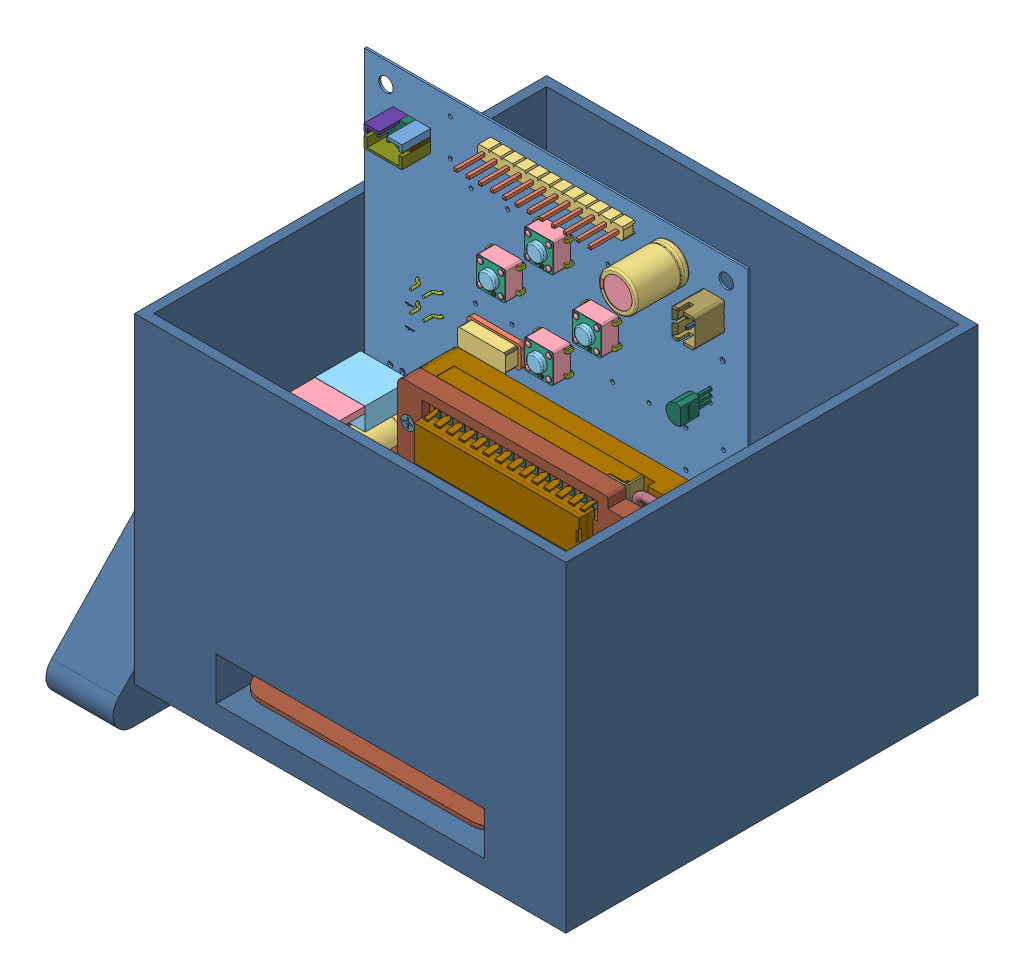
SolidWorks assembly Assem1, configuration Default. Lengths in mm.
Overall size (108 107.56 86.98).
167 component instances, 47 part files, 0 mates.
Components (placement in the parent):
- Clock PCB.step-1: Clock PCB.step [Default] at (-3.837 -6.133 58.5856) size (81.95 80 25.5)
  - Board.step-1: Board.step [Default] at origin size (80 80 0.41)
    - Open CASCADE STEP translator 6.8 1.1.1.step-1: Open CASCADE STEP translator 6.8 1.1.1.step [Default] at (0 0 -0.4115) size (80 80 0.41)
  - XTAL1.step-1: XTAL1.step [Default] at origin size (11.36 4.66 3.61)
    - 6606830048.step-1: 6606830048.step [Default] at (28.0499 41.0499 0) size (11.36 4.66 1.01)
      - Extruded.step-1: Extruded.step [Default] at origin size (11.36 4.66 1.01)
    - 6606829968.step-1: 6606829968.step [Default] at (28.0499 41.0501 1) size (10.05 3.71 2.61)
      - Extruded-0.step-1: Extruded-0.step [Default] at origin size (10.05 3.71 2.61)
  - U2.step-1: U2.step [Default] at origin size (10.5 4.7 16.2)
    - 6606829888.step-1: 6606829888.step [Default] at (7.95 27.55 13.05) size (10.4 1.3 6.65)
      - Extruded-1.step-1: Extruded-1.step [Default] at origin size (10.4 1.3 6.65)
    - 6606829728.step-1: 6606829728.step [Default] at (7.95 25.9 3.5) size (10.5 4.7 9.55)
      - Extruded-2.step-1: Extruded-2.step [Default] at origin size (10.5 4.7 9.55)
  - U1.step-1: U1.step [Default] at origin size (63.7 16.03 14.45)
    - User_Library-ZIF-Socket-28-pin.step-1: User_Library-ZIF-Socket-28-pin.step [Default] at (43.5 28.05 0) x (1 0 0) z (0 0 1) size (63.7 16.03 14.45)
      - Contacts.step-1: Contacts.step [Default] at origin size (34.37 11.24 1.5)
      - Pins001.step-1: Pins001.step [Default] at origin size (33.87 8.47 3)
      - Screw002.step-1: Screw002.step [Default] at origin size (2.8 2.8 2)
      - Bottom-Shape.step-1: Bottom-Shape.step [Default] at origin size (50.4 15.02 8.11)
      - Lever-Tip.step-1: Lever-Tip.step [Default] at origin size (7 4.8 4.8)
      - Top-Shape.step-1: Top-Shape.step [Default] at origin size (50.4 15.02 3.8)
      - Push-Bar.step-1: Push-Bar.step [Default] at origin size (3.85 15.02 3.7)
      - Lever-Bar.step-1: Lever-Bar.step [Default] at origin size (19.2 11.43 1.62)
      - Screw001.step-1: Screw001.step [Default] at origin size (2.8 2.8 2)
  - Q1.step-1: Q1.step [Default] at origin size (3.05 4.08 12.8)
    - BC547-B.step-1: BC547-B.step [Default] at (72 53.1536 7) x (0 1 0) z (0 0 -1) size (4.08 3.05 12.8)
  - P3.step-1: P3.step [Default] at origin size (2.54 10.16 11.54)
    - 61300411121.step-1: 61300411121.step [Default] at (76.2999 22.6001 1.3) x (0 1 0) z (1 0 0) size (10.16 11.54 2.54)
      - 6130xx11121_PIN.step-1: 6130xx11121_PIN.step [Default] at (-3.81 1.5 0) x (1 0 0) z (0 -1 0) size (0.64 0.64 11.54)
      - 6130xx11121_PIN.step-2: 6130xx11121_PIN.step [Default] at (-1.27 1.5 0) x (1 0 0) z (0 -1 0) size (0.64 0.64 11.54)
      - 6130xx11121_PIN.step-3: 6130xx11121_PIN.step [Default] at (1.27 1.5 0) x (1 0 0) z (0 -1 0) size (0.64 0.64 11.54)
      - 6130xx11121_PIN.step-4: 6130xx11121_PIN.step [Default] at (3.81 1.5 0) x (1 0 0) z (0 -1 0) size (0.64 0.64 11.54)
      - 61300411121-3.step-1: 61300411121-3.step [Default] at origin size (10.16 2.54 2.54)
  - P2.step-1: P2.step [Default] at origin size (17.78 2.54 11.54)
    - 61300711121.step-1: 61300711121.step [Default] at (39.9599 3.8999 1.3) x (-1 0 0) z (0 1 0) size (17.78 11.54 2.54)
      - 6130xx11121_PIN-4.step-1: 6130xx11121_PIN-4.step [Default] at (-7.62 1.5 0) x (1 0 0) z (0 -1 0) size (0.64 0.64 11.54)
      - 6130xx11121_PIN-4.step-2: 6130xx11121_PIN-4.step [Default] at (-5.08 1.5 0) x (1 0 0) z (0 -1 0) size (0.64 0.64 11.54)
      - 6130xx11121_PIN-4.step-3: 6130xx11121_PIN-4.step [Default] at (-2.54 1.5 0) x (1 0 0) z (0 -1 0) size (0.64 0.64 11.54)
      - 6130xx11121_PIN-4.step-4: 6130xx11121_PIN-4.step [Default] at (0 1.5 0) x (1 0 0) z (0 -1 0) size (0.64 0.64 11.54)
      - 6130xx11121_PIN-4.step-5: 6130xx11121_PIN-4.step [Default] at (2.54 1.5 0) x (1 0 0) z (0 -1 0) size (0.64 0.64 11.54)
      - 6130xx11121_PIN-4.step-6: 6130xx11121_PIN-4.step [Default] at (5.08 1.5 0) x (1 0 0) z (0 -1 0) size (0.64 0.64 11.54)
      - 6130xx11121_PIN-4.step-7: 6130xx11121_PIN-4.step [Default] at (7.62 1.5 0) x (1 0 0) z (0 -1 0) size (0.64 0.64 11.54)
      - 61300711121-5.step-1: 61300711121-5.step [Default] at origin size (17.78 2.54 2.54)
  - P1.step-1: P1.step [Default] at origin size (30.48 2.54 11.54)
    - 61301211121.step-1: 61301211121.step [Default] at (41.3799 75.6999 1.3) x (-1 0 0) z (0 1 0) size (30.48 11.54 2.54)
      - 6130xx11121_PIN-6.step-1: 6130xx11121_PIN-6.step [Default] at (-13.97 1.5 0) x (1 0 0) z (0 -1 0) size (0.64 0.64 11.54)
      - 6130xx11121_PIN-6.step-2: 6130xx11121_PIN-6.step [Default] at (-11.43 1.5 0) x (1 0 0) z (0 -1 0) size (0.64 0.64 11.54)
      - 6130xx11121_PIN-6.step-3: 6130xx11121_PIN-6.step [Default] at (-8.89 1.5 0) x (1 0 0) z (0 -1 0) size (0.64 0.64 11.54)
      - 6130xx11121_PIN-6.step-4: 6130xx11121_PIN-6.step [Default] at (-6.35 1.5 0) x (1 0 0) z (0 -1 0) size (0.64 0.64 11.54)
      - 6130xx11121_PIN-6.step-5: 6130xx11121_PIN-6.step [Default] at (-3.81 1.5 0) x (1 0 0) z (0 -1 0) size (0.64 0.64 11.54)
      - 6130xx11121_PIN-6.step-6: 6130xx11121_PIN-6.step [Default] at (-1.27 1.5 0) x (1 0 0) z (0 -1 0) size (0.64 0.64 11.54)
      - 6130xx11121_PIN-6.step-7: 6130xx11121_PIN-6.step [Default] at (1.27 1.5 0) x (1 0 0) z (0 -1 0) size (0.64 0.64 11.54)
      - 6130xx11121_PIN-6.step-8: 6130xx11121_PIN-6.step [Default] at (3.81 1.5 0) x (1 0 0) z (0 -1 0) size (0.64 0.64 11.54)
      - 6130xx11121_PIN-6.step-9: 6130xx11121_PIN-6.step [Default] at (6.35 1.5 0) x (1 0 0) z (0 -1 0) size (0.64 0.64 11.54)
      - 6130xx11121_PIN-6.step-10: 6130xx11121_PIN-6.step [Default] at (8.89 1.5 0) x (1 0 0) z (0 -1 0) size (0.64 0.64 11.54)
      - 6130xx11121_PIN-6.step-11: 6130xx11121_PIN-6.step [Default] at (11.43 1.5 0) x (1 0 0) z (0 -1 0) size (0.64 0.64 11.54)
      - 6130xx11121_PIN-6.step-12: 6130xx11121_PIN-6.step [Default] at (13.97 1.5 0) x (1 0 0) z (0 -1 0) size (0.64 0.64 11.54)
      - 61301211121-7.step-1: 61301211121-7.step [Default] at origin size (30.48 2.54 2.54)
  - KEY5.step-1: KEY5.step [Default] at origin size (7.8 5.99 8.11)
    - Switch_TE_1825910-2_eec.step-1: Switch_TE_1825910-2_eec.step [Default] at (68.1 13.85 0) size (7.8 5.99 8.11)
      - Body.step-1: Body.step [Default] at (0 0 4.3) x (0 -1 0) z (0 0 1) size (5.99 5.99 3.9)
      - button.step-1: button.step [Default] at (0 0 4.3) x (0 -1 0) z (0 0 1) size (3.51 3.51 1.1)
      - cover.step-1: cover.step [Default] at (0 0 4.3) x (0 -1 0) z (0 0 1) size (5.99 5.99 0.1)
      - leads.step-1: leads.step [Default] at (0 0 4.3) x (0 -1 0) z (0 0 1) size (5.21 7.8 4.81)
      - circle.step-1: circle.step [Default] at (-2.6803 2.6863 3.6) size (0.4 0.4 0)
      - TE_Connectivity.step-1: TE_Connectivity.step [Default] at (-0.1925 -2.4218 3.6) size (2.27 0.85 0.01)
  - KEY4.step-1: KEY4.step [Default] at origin size (7.8 5.99 8.11)
    - Switch_TE_1825910-2_eec.step-1: Switch_TE_1825910-2_eec.step [Default] at (50 55 0) size (7.8 5.99 8.11)
      - Body.step-1: Body.step [Default] at (0 0 4.3) x (0 -1 0) z (0 0 1) size (5.99 5.99 3.9)
      - button.step-1: button.step [Default] at (0 0 4.3) x (0 -1 0) z (0 0 1) size (3.51 3.51 1.1)
      - cover.step-1: cover.step [Default] at (0 0 4.3) x (0 -1 0) z (0 0 1) size (5.99 5.99 0.1)
      - leads.step-1: leads.step [Default] at (0 0 4.3) x (0 -1 0) z (0 0 1) size (5.21 7.8 4.81)
      - circle.step-1: circle.step [Default] at (-2.6803 2.6863 3.6) size (0.4 0.4 0)
      - TE_Connectivity.step-1: TE_Connectivity.step [Default] at (-0.1925 -2.4218 3.6) size (2.27 0.85 0.01)
  - KEY3.step-1: KEY3.step [Default] at origin size (7.8 5.99 8.11)
    - Switch_TE_1825910-2_eec.step-1: Switch_TE_1825910-2_eec.step [Default] at (30 55 0) size (7.8 5.99 8.11)
      - Body.step-1: Body.step [Default] at (0 0 4.3) x (0 -1 0) z (0 0 1) size (5.99 5.99 3.9)
      - button.step-1: button.step [Default] at (0 0 4.3) x (0 -1 0) z (0 0 1) size (3.51 3.51 1.1)
      - cover.step-1: cover.step [Default] at (0 0 4.3) x (0 -1 0) z (0 0 1) size (5.99 5.99 0.1)
      - leads.step-1: leads.step [Default] at (0 0 4.3) x (0 -1 0) z (0 0 1) size (5.21 7.8 4.81)
      - circle.step-1: circle.step [Default] at (-2.6803 2.6863 3.6) size (0.4 0.4 0)
      - TE_Connectivity.step-1: TE_Connectivity.step [Default] at (-0.1925 -2.4218 3.6) size (2.27 0.85 0.01)
  - KEY2.step-1: KEY2.step [Default] at origin size (7.8 5.99 8.11)
    - Switch_TE_1825910-2_eec.step-1: Switch_TE_1825910-2_eec.step [Default] at (40 45 0) size (7.8 5.99 8.11)
      - Body.step-1: Body.step [Default] at (0 0 4.3) x (0 -1 0) z (0 0 1) size (5.99 5.99 3.9)
      - button.step-1: button.step [Default] at (0 0 4.3) x (0 -1 0) z (0 0 1) size (3.51 3.51 1.1)
      - cover.step-1: cover.step [Default] at (0 0 4.3) x (0 -1 0) z (0 0 1) size (5.99 5.99 0.1)
      - leads.step-1: leads.step [Default] at (0 0 4.3) x (0 -1 0) z (0 0 1) size (5.21 7.8 4.81)
      - circle.step-1: circle.step [Default] at (-2.6803 2.6863 3.6) size (0.4 0.4 0)
      - TE_Connectivity.step-1: TE_Connectivity.step [Default] at (-0.1925 -2.4218 3.6) size (2.27 0.85 0.01)
  - KEY1.step-1: KEY1.step [Default] at origin size (7.8 5.99 8.11)
    - Switch_TE_1825910-2_eec.step-1: Switch_TE_1825910-2_eec.step [Default] at (40 65 0) size (7.8 5.99 8.11)
      - Body.step-1: Body.step [Default] at (0 0 4.3) x (0 -1 0) z (0 0 1) size (5.99 5.99 3.9)
      - button.step-1: button.step [Default] at (0 0 4.3) x (0 -1 0) z (0 0 1) size (3.51 3.51 1.1)
      - cover.step-1: cover.step [Default] at (0 0 4.3) x (0 -1 0) z (0 0 1) size (5.99 5.99 0.1)
      - leads.step-1: leads.step [Default] at (0 0 4.3) x (0 -1 0) z (0 0 1) size (5.21 7.8 4.81)
      - circle.step-1: circle.step [Default] at (-2.6803 2.6863 3.6) size (0.4 0.4 0)
      - TE_Connectivity.step-1: TE_Connectivity.step [Default] at (-0.1925 -2.4218 3.6) size (2.27 0.85 0.01)
  - JST2.step-1: JST2.step [Default] at origin size (4.7 6 10.05)
    - Conn_TE_Connectivity_440054-2_eec.step-1: Conn_TE_Connectivity_440054-2_eec.step [Default] at (72.85 68.85 0) x (0 -1 0) z (0 0 1) size (6 4.7 10.05)
      - 1.step-1: 1.step [Default] at (0 -0.6 6.05) size (2.5 2.35 8.8)
      - 2.step-1: 2.step [Default] at (0 -0.6 6.05) size (0.9 0.1 1.08)
      - 3.step-1: 3.step [Default] at (0 -0.6 6.05) size (6 4.7 6.35)
      - TE_connectivity_Logo_1_(2).step-1: TE_connectivity_Logo_1_(2).step [Default] at (2.901 6.9182 0.6322) x (0 -1 0) z (1 0 0) size (1.49 0.53 0.1)
  - JST1.step-1: JST1.step [Default] at origin size (6 4.7 10.05)
    - Conn_TE_Connectivity_440054-2_eec.step-1: Conn_TE_Connectivity_440054-2_eec.step [Default] at (10.55 4.25 0) x (-1 0 0) z (0 0 1) size (6 4.7 10.05)
      - 1.step-1: 1.step [Default] at (0 -0.6 6.05) size (2.5 2.35 8.8)
      - 2.step-1: 2.step [Default] at (0 -0.6 6.05) size (0.9 0.1 1.08)
      - 3.step-1: 3.step [Default] at (0 -0.6 6.05) size (6 4.7 6.35)
      - TE_connectivity_Logo_1_(2).step-1: TE_connectivity_Logo_1_(2).step [Default] at (2.901 6.9182 0.6322) x (0 -1 0) z (1 0 0) size (1.49 0.53 0.1)
  - JST3.step-1: JST3.step [Default] at origin size (7.9 4.5 9.4)
    - 6606829248.step-1: 6606829248.step [Default] at (11.9 70.55 -3.4) size (0.5 0.5 8.45)
      - Extruded-8.step-1: Extruded-8.step [Default] at origin size (0.5 0.5 8.45)
    - 6606829248.step-2: 6606829248.step [Default] at (7.9 70.55 -3.4) size (0.5 0.5 8.45)
      - Extruded-8.step-1: Extruded-8.step [Default] at origin size (0.5 0.5 8.45)
    - 6606829248.step-3: 6606829248.step [Default] at (9.9 70.55 -3.4) size (0.5 0.5 8.45)
      - Extruded-8.step-1: Extruded-8.step [Default] at origin size (0.5 0.5 8.45)
    - 6606828928.step-1: 6606828928.step [Default] at (9.9 70.2 0) size (6.6 4.1 1.75)
      - Extruded-9.step-1: Extruded-9.step [Default] at origin size (6.6 4.1 1.75)
    - 6606828768.step-1: 6606828768.step [Default] at (9.9 68.875 0) size (7.9 2.25 6)
      - Extruded-10.step-1: Extruded-10.step [Default] at origin size (7.9 2.25 6)
    - 6606828608.step-1: 6606828608.step [Default] at (7.525 71.525 0) size (3.15 1.45 6)
      - Extruded-11.step-1: Extruded-11.step [Default] at origin size (3.15 1.45 6)
    - 6606828448.step-1: 6606828448.step [Default] at (6.275 70.4 0) size (0.65 0.8 4.1)
      - Extruded-12.step-1: Extruded-12.step [Default] at origin size (0.65 0.8 4.1)
    - 6606828448.step-2: 6606828448.step [Default] at (13.525 70.4 0) size (0.65 0.8 4.1)
      - Extruded-12.step-1: Extruded-12.step [Default] at origin size (0.65 0.8 4.1)
    - 6606828208.step-1: 6606828208.step [Default] at (12.275 71.525 0) size (3.15 1.45 6)
      - Extruded-13.step-1: Extruded-13.step [Default] at origin size (3.15 1.45 6)
  - C6.step-1: C6.step [Default] at origin size (8 8 14.5)
    - Aluminum_electrolytic_capacitor_radial_D8_H11.5_PinD0.6_Pitch3.5_nominal_black.step-1: Aluminum_electrolytic_capacitor_radial_D8_H11.5_PinD0.6_Pitch3.5_nominal_black.step [Default] at (64.35 73.55 0) x (-1 0 0) z (0 0 1) size (1.1 2.07 11.1)
    - Aluminum_electrolytic_capacitor_radial_D8_H11.5_PinD0.6_Pitch3.5_nominal_black-14.step-1: Aluminum_electrolytic_capacitor_radial_D8_H11.5_PinD0.6_Pitch3.5_nominal_black-14.step [Default] at (64.35 73.55 0) x (-1 0 0) z (0 0 1) size (7.86 8 11.1)
    - Aluminum_electrolytic_capacitor_radial_D8_H11.5_PinD0.6_Pitch3.5_nominal_black-15.step-1: Aluminum_electrolytic_capacitor_radial_D8_H11.5_PinD0.6_Pitch3.5_nominal_black-15.step [Default] at (64.35 73.55 0) x (-1 0 0) z (0 0 1) size (7.8 7.8 10.9)
    - Aluminum_electrolytic_capacitor_radial_D8_H11.5_PinD0.6_Pitch3.5_nominal_black-16.step-1: Aluminum_electrolytic_capacitor_radial_D8_H11.5_PinD0.6_Pitch3.5_nominal_black-16.step [Default] at (64.35 73.55 0) x (-1 0 0) z (0 0 1) size (7.4 7.4 1.6)
    - Aluminum_electrolytic_capacitor_radial_D8_H11.5_PinD0.6_Pitch3.5_nominal_black-17.step-1: Aluminum_electrolytic_capacitor_radial_D8_H11.5_PinD0.6_Pitch3.5_nominal_black-17.step [Default] at (64.35 73.55 0) x (-1 0 0) z (0 0 1) size (4.1 0.6 3)
  - C5.step-1: C5.step [Default] at origin size (8 8 14.5)
    - Aluminum_electrolytic_capacitor_radial_D8_H11.5_PinD0.6_Pitch3.5_nominal_black.step-1: Aluminum_electrolytic_capacitor_radial_D8_H11.5_PinD0.6_Pitch3.5_nominal_black.step [Default] at (65.05 5.25 0) size (1.1 2.07 11.1)
    - Aluminum_electrolytic_capacitor_radial_D8_H11.5_PinD0.6_Pitch3.5_nominal_black-14.step-1: Aluminum_electrolytic_capacitor_radial_D8_H11.5_PinD0.6_Pitch3.5_nominal_black-14.step [Default] at (65.05 5.25 0) size (7.86 8 11.1)
    - Aluminum_electrolytic_capacitor_radial_D8_H11.5_PinD0.6_Pitch3.5_nominal_black-15.step-1: Aluminum_electrolytic_capacitor_radial_D8_H11.5_PinD0.6_Pitch3.5_nominal_black-15.step [Default] at (65.05 5.25 0) size (7.8 7.8 10.9)
    - Aluminum_electrolytic_capacitor_radial_D8_H11.5_PinD0.6_Pitch3.5_nominal_black-16.step-1: Aluminum_electrolytic_capacitor_radial_D8_H11.5_PinD0.6_Pitch3.5_nominal_black-16.step [Default] at (65.05 5.25 0) size (7.4 7.4 1.6)
    - Aluminum_electrolytic_capacitor_radial_D8_H11.5_PinD0.6_Pitch3.5_nominal_black-17.step-1: Aluminum_electrolytic_capacitor_radial_D8_H11.5_PinD0.6_Pitch3.5_nominal_black-17.step [Default] at (65.05 5.25 0) size (4.1 0.6 3)
  - C4.step-1: C4.step [Default] at origin size (5.99 5.99 8.89)
    - Cap_Murata_RCE5C2A3R0C0K1H03B_eec.step-1: Cap_Murata_RCE5C2A3R0C0K1H03B_eec.step [Default] at (13.7 39.4 0) x (1 0 0) z (0 0 1) size (5.99 5.99 8.89)
      - Body.step-1: Body.step [Default] at origin size (5.99 5.99 3.9)
      - leads-18.step-1: leads-18.step [Default] at origin size (5.5 0.5 6.65)
      - logo.step-1: logo.step [Default] at (0 -1.25 8.5) x (1 0 0) z (0 -1 0) size (1.98 0.46 0.01)
  - C3.step-1: C3.step [Default] at origin size (5.99 5.99 8.89)
    - Cap_Murata_RCE5C2A3R0C0K1H03B_eec.step-1: Cap_Murata_RCE5C2A3R0C0K1H03B_eec.step [Default] at (13.65 43.7 0) x (1 0 0) z (0 0 1) size (5.99 5.99 8.89)
      - Body.step-1: Body.step [Default] at origin size (5.99 5.99 3.9)
      - leads-18.step-1: leads-18.step [Default] at origin size (5.5 0.5 6.65)
      - logo.step-1: logo.step [Default] at (0 -1.25 8.5) x (1 0 0) z (0 -1 0) size (1.98 0.46 0.01)
  - C2.step-1: C2.step [Default] at origin size (8 8 14.5)
    - Aluminum_electrolytic_capacitor_radial_D8_H11.5_PinD0.6_Pitch3.5_nominal_black.step-1: Aluminum_electrolytic_capacitor_radial_D8_H11.5_PinD0.6_Pitch3.5_nominal_black.step [Default] at (17.55 14.1 0) size (1.1 2.07 11.1)
    - Aluminum_electrolytic_capacitor_radial_D8_H11.5_PinD0.6_Pitch3.5_nominal_black-14.step-1: Aluminum_electrolytic_capacitor_radial_D8_H11.5_PinD0.6_Pitch3.5_nominal_black-14.step [Default] at (17.55 14.1 0) size (7.86 8 11.1)
    - Aluminum_electrolytic_capacitor_radial_D8_H11.5_PinD0.6_Pitch3.5_nominal_black-15.step-1: Aluminum_electrolytic_capacitor_radial_D8_H11.5_PinD0.6_Pitch3.5_nominal_black-15.step [Default] at (17.55 14.1 0) size (7.8 7.8 10.9)
    - Aluminum_electrolytic_capacitor_radial_D8_H11.5_PinD0.6_Pitch3.5_nominal_black-16.step-1: Aluminum_electrolytic_capacitor_radial_D8_H11.5_PinD0.6_Pitch3.5_nominal_black-16.step [Default] at (17.55 14.1 0) size (7.4 7.4 1.6)
    - Aluminum_electrolytic_capacitor_radial_D8_H11.5_PinD0.6_Pitch3.5_nominal_black-17.step-1: Aluminum_electrolytic_capacitor_radial_D8_H11.5_PinD0.6_Pitch3.5_nominal_black-17.step [Default] at (17.55 14.1 0) size (4.1 0.6 3)
  - C1.step-1: C1.step [Default] at origin size (8 8 14.5)
    - Aluminum_electrolytic_capacitor_radial_D8_H11.5_PinD0.6_Pitch3.5_nominal_black.step-1: Aluminum_electrolytic_capacitor_radial_D8_H11.5_PinD0.6_Pitch3.5_nominal_black.step [Default] at (7.05 14.5 0) size (1.1 2.07 11.1)
    - Aluminum_electrolytic_capacitor_radial_D8_H11.5_PinD0.6_Pitch3.5_nominal_black-14.step-1: Aluminum_electrolytic_capacitor_radial_D8_H11.5_PinD0.6_Pitch3.5_nominal_black-14.step [Default] at (7.05 14.5 0) size (7.86 8 11.1)
    - Aluminum_electrolytic_capacitor_radial_D8_H11.5_PinD0.6_Pitch3.5_nominal_black-15.step-1: Aluminum_electrolytic_capacitor_radial_D8_H11.5_PinD0.6_Pitch3.5_nominal_black-15.step [Default] at (7.05 14.5 0) size (7.8 7.8 10.9)
    - Aluminum_electrolytic_capacitor_radial_D8_H11.5_PinD0.6_Pitch3.5_nominal_black-16.step-1: Aluminum_electrolytic_capacitor_radial_D8_H11.5_PinD0.6_Pitch3.5_nominal_black-16.step [Default] at (7.05 14.5 0) size (7.4 7.4 1.6)
    - Aluminum_electrolytic_capacitor_radial_D8_H11.5_PinD0.6_Pitch3.5_nominal_black-17.step-1: Aluminum_electrolytic_capacitor_radial_D8_H11.5_PinD0.6_Pitch3.5_nominal_black-17.step [Default] at (7.05 14.5 0) size (4.1 0.6 3)
  - Free-Models.step-1: Free-Models.step [Default] at origin size (34.6 9.68 7.3)
    - atmega328p-pu.step-1: atmega328p-pu.step [Default] at (59.217 28 11) x (-1 0 0) z (0 1 0) size (34.6 7.3 9.68)
- Part46^Assem1-1: Part46^Assem1 [Default] at origin size (108 78.56 86.98) (virtual)
- Matrix Keypad 12 Key (4X3)-3: Matrix Keypad 12 Key (4X3) [Default] at (36.4996 -15.5363 60.1938) x (1 0 0) z (0 1 0) size (54 77 1.31)
